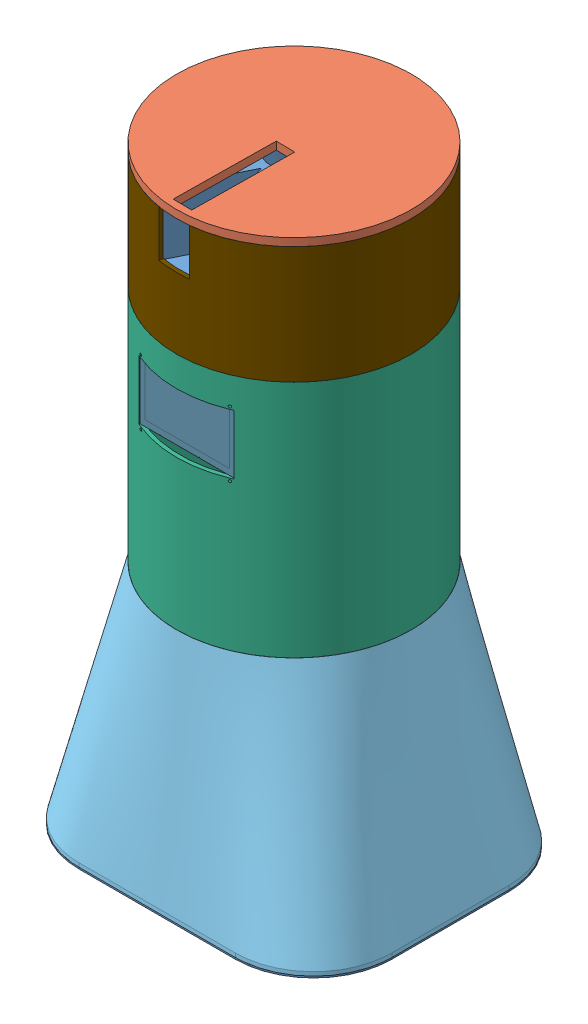
SolidWorks assembly Main Assembly, configuration Default. Lengths in mm.
Overall size (428.69 805.97 406.23).
32 component instances, 21 part files, 30 mates.
Components (placement in the parent):
- Base-1: Base [Default] at (-9.7695 -23.298 20.3041) size (400 2 350)
- Wheel-1: Wheel [Default] at (-159.7695 3.702 20.3041) x (0 -0.4051 0.914272) z (-1 0 0) size (100 100 35)
- Wheel-2: Wheel [Default] at (140.2305 3.702 20.3041) x (0 0.318897 -0.947789) z (1 0 0) size (100 100 35)
- MINEBEA 05701607 stepper motor.step-1: MINEBEA 05701607 stepper motor.step [Default] at (-120.6195 3.702 20.3041) x (0 0 -1) z (-1 0 0) size (42 48.2 62.55)
- MINEBEA 05701607 stepper motor.step-2: MINEBEA 05701607 stepper motor.step [Default] at (101.0805 3.702 20.3041) x (0 0 1) z (1 0 0) size (42 48.2 62.55)
- Nema 17 bracket-1: Nema 17 bracket [Default] at (-122.6195 3.702 20.3041) x (0 0 1) z (-1 0 0) size (40 50 40)
- Nema 17 bracket-2: Nema 17 bracket [Default] at (103.0805 3.702 20.3041) x (0 0 -1) z (1 0 0) size (40 50 40)
- Base Cover-1: Base Cover [Default] at (-9.7695 -21.298 20.3041) size (428.69 300.01 378.81)
- Mid Cover-1: Mid Cover [Default] at (-9.7695 278.702 20.3041) size (300 305 300)
- ER-TFTV050A3-3_3D.step-2: ER-TFTV050A3-3_3D.step [Default] at (-66.6994 466.0367 151.0649) size (121.88 89.8 12.7)
  - Default.step-1: Default.step [Default] at origin size (121.88 89.8 12.7)
    - Micro-USB-1.step-1: Micro-USB-1.step [Default] at (115.1584 26.8063 -1.07) x (0 -1 0) z (1 0 0) size (7.98 2.76 5.43)
    - Micro-USB-1.step-2: Micro-USB-1.step [Default] at (115.1026 41.8572 -1.07) x (0 -1 0) z (1 0 0) size (7.98 2.76 5.43)
    - HDMI_卡座-1.step-1: HDMI_卡座-1.step [Default] at (118.3814 62.6862 -1.07) x (0 -1 0) z (1 0 0) size (15.08 8.38 12.15)
    - XPT2046-1.step-1: XPT2046-1.step [Default] at (96.2836 29.7423 -0.098) x (0 -1 0) z (0 0 -1) size (5.58 5.58 1.35)
    - XPT2046-1.step-2: XPT2046-1.step [Default] at (96.7433 37.2781 -0.098) x (0 -1 0) z (0 0 -1) size (5.58 5.58 1.35)
    - 连接器_50-Pin-1.step-1: 连接器_50-Pin-1.step [Default] at (33.4715 47.6211 -0.8) x (1 0 0) z (0 0 -1) size (25.97 6.45 2.13)
    - 拨动开关-2.step-1: 拨动开关-2.step [Default] at (109.6588 14.0139 -2.551) x (0 1 0) z (1 0 0) size (9.25 3.5 8.04)
    - FLASH_IC-1.step-1: FLASH_IC-1.step [Default] at (50.1709 65.5261 -1.6531) x (0 -1 0) z (1 0 0) size (5.63 2.58 8.9)
    - 043A3-050A3-3 IC-2.step-1: 043A3-050A3-3 IC-2.step [Default] at (61.6363 43.8941 -1) x (0 -1 0) z (1 0 0) size (24.4 2.6 19.54)
    - V050A3-3-1.step-1: V050A3-3-1.step [Default] at origin size (120.9 89.8 7)
    - 连接器_6-Pin-1.step-1: 连接器_6-Pin-1.step [Default] at (81.4816 49.8598 -0.8) x (-1 0 0) z (0 0 -1) size (10.37 5.52 2)
    - ER-TFTV043A3-3开关 - 副本-1.step-1: ER-TFTV043A3-3开关 - 副本-1.step [Default] at (0.6995 12.4598 -2.2219) x (0 0 1) z (-1 0 0) size (2.85 7.04 5.23)
    - ER-TFTV043A3-3开关 - 副本-1.step-2: ER-TFTV043A3-3开关 - 副本-1.step [Default] at (0.6995 23.4598 -2.2219) x (0 0 1) z (-1 0 0) size (2.85 7.04 5.23)
    - ER-TFTV043A3-3开关 - 副本-1.step-3: ER-TFTV043A3-3开关 - 副本-1.step [Default] at (0.6995 34.4598 -2.2219) x (0 0 1) z (-1 0 0) size (2.85 7.04 5.23)
    - ER-TFTV043A3-3开关 - 副本-1.step-4: ER-TFTV043A3-3开关 - 副本-1.step [Default] at (0.6995 45.4598 -2.2219) x (0 0 1) z (-1 0 0) size (2.85 7.04 5.23)
- Mid Plate-1: Mid Plate [Default] at (-9.7695 285.702 20.3041) x (1 0 0) z (0 -1 0) size (288 288 2)
- dispenser-1: dispenser [Default] at (276.6087 461.337 -65.9211) x (-0.098072 0 0.995179) z (-0.995179 0 -0.098072) size (371.58 150 371.58)
  - medicine dispenser shwll-1: medicine dispenser shwll [Default] at (113.8952 122.365 276.5413) x (1 0 0) z (0 1 0) size (300 300 150)
  - medicine dispenser roatating part-1: medicine dispenser roatating part [Default] at (113.8952 177.365 276.5413) x (0.934657 0 0.35555) z (-0.35555 0 0.934657) size (288 94 288)
  - medicine dispenser lid-1: medicine dispenser lid [Default] at (113.8952 272.365 276.5413) x (0.085182 0 0.996365) z (-0.996365 0 0.085182) size (300 10 300)
- rod-1: rod [Default] at (-9.5195 278.702 20.0541) size (20 600 20)
Mates (geometry in assembly coordinates):
- Coincident1: coincident anti-aligned: plane of Base-1 through (-9.7695 -21.298 20.3041) normal (0 1 0); plane of Nema 17 bracket-1 through (-122.6195 -21.298 20.3041) normal (0 -1 0)
- Concentric1: concentric aligned: cylinder of MINEBEA 05701607 stepper motor.step-1 through (-120.6195 -11.798 35.8041) axis (1 0 0) radius 1.25; cylinder of Nema 17 bracket-1 through (-122.6205 -11.798 35.8041) axis (1 0 0) radius 1.4
- Concentric2: concentric aligned: cylinder of MINEBEA 05701607 stepper motor.step-1 through (-120.6195 19.202 4.8041) axis (1 0 0) radius 1.25; cylinder of Nema 17 bracket-1 through (-122.6205 19.202 4.8041) axis (1 0 0) radius 1.4
- Coincident2: coincident anti-aligned: plane of MINEBEA 05701607 stepper motor.step-1 through (-120.6195 3.702 20.3041) normal (-1 0 0); plane of Nema 17 bracket-1 through (-120.6195 3.702 20.3041) normal (1 0 0)
- Concentric3: concentric aligned: cylinder of Wheel-1 through (-169.7705 3.702 20.3041) axis (1 0 0) radius 3; cylinder of MINEBEA 05701607 stepper motor.step-1 through (-144.7695 3.702 20.3041) axis (1 0 0) radius 2.5
- Distance1: distance = 10 mm anti-aligned: plane of Wheel-1 through (-134.7695 3.702 20.3041) normal (1 0 0); plane of MINEBEA 05701607 stepper motor.step-1 through (-144.7695 3.702 20.3041) normal (-1 0 0)
- Width1: width anti-aligned: plane of Base-1 through (-144.7695 -23.299 -54.6959) normal (-1 0 0); plane of Wheel-1 through (-174.7695 -23.299 -54.6959) normal (1 0 0); plane of Base-1 through (-149.7695 3.702 20.3041) normal (1 0 0); plane of Wheel-1 through (-169.7695 3.702 20.3041) normal (-1 0 0)
- Width2: width aligned: plane of Base-1 through (-209.7695 -21.298 195.3041) normal (0 0 1); plane of Nema 17 bracket-1 through (-209.7695 -21.298 -154.6959) normal (0 0 -1); plane of Base-1 through (-120.6195 -21.298 40.3041) normal (0 0 1); plane of Nema 17 bracket-1 through (-82.6195 -21.298 0.3041) normal (0 0 -1)
- Width3: width aligned: plane of Base-1 through (-209.7695 -21.298 195.3041) normal (0 0 1); plane of Nema 17 bracket-2 through (-209.7695 -21.298 -154.6959) normal (0 0 -1); plane of Base-1 through (63.0805 -21.298 40.3041) normal (0 0 1); plane of Nema 17 bracket-2 through (101.0805 -21.298 0.3041) normal (0 0 -1)
- Coincident3: coincident anti-aligned: plane of Base-1 through (-9.7695 -21.298 20.3041) normal (0 1 0); plane of Nema 17 bracket-2 through (103.0805 -21.298 20.3041) normal (0 -1 0)
- Concentric4: concentric aligned: cylinder of MINEBEA 05701607 stepper motor.step-2 through (101.0805 -11.798 4.8041) axis (-1 0 0) radius 1.25; cylinder of Nema 17 bracket-2 through (103.0815 -11.798 4.8041) axis (-1 0 0) radius 1.4
- Concentric5: concentric aligned: cylinder of MINEBEA 05701607 stepper motor.step-2 through (101.0805 19.202 35.8041) axis (-1 0 0) radius 1.25; cylinder of Nema 17 bracket-2 through (103.0815 19.202 35.8041) axis (-1 0 0) radius 1.4
- Coincident4: coincident anti-aligned: plane of MINEBEA 05701607 stepper motor.step-2 through (101.0805 3.702 20.3041) normal (1 0 0); plane of Nema 17 bracket-2 through (101.0805 3.702 20.3041) normal (-1 0 0)
- Concentric6: concentric aligned: cylinder of Wheel-2 through (150.2315 3.702 20.3041) axis (-1 0 0) radius 3; cylinder of MINEBEA 05701607 stepper motor.step-2 through (125.2305 3.702 20.3041) axis (-1 0 0) radius 2.5
- Distance2: distance = 10 mm anti-aligned: plane of Wheel-2 through (115.2305 3.702 20.3041) normal (-1 0 0); plane of MINEBEA 05701607 stepper motor.step-2 through (125.2305 3.702 20.3041) normal (1 0 0)
- Width4: width anti-aligned: plane of Base-1 through (125.2305 -23.299 -54.6959) normal (1 0 0); plane of Wheel-2 through (155.2305 -23.299 -54.6959) normal (-1 0 0); plane of Base-1 through (130.2305 3.702 20.3041) normal (-1 0 0); plane of Wheel-2 through (150.2305 3.702 20.3041) normal (1 0 0)
- Coincident5: coincident anti-aligned: plane of Base-1 through (-9.7695 -21.298 20.3041) normal (0 1 0); plane of Base Cover-1 through (90.2305 -21.298 95.3041) normal (0 -1 0)
- Coincident6: coincident aligned: plane of Base-1 through (-209.7695 -21.298 195.3041) normal (0 0 1); plane of Base Cover-1 through (-109.7695 -16.298 195.3041) normal (0 0 1)
- Coincident7: coincident aligned: plane of Base-1 through (190.2305 -21.298 -154.6959) normal (1 0 0); plane of Base Cover-1 through (190.2305 -16.298 -54.6959) normal (1 0 0)
- Concentric7: concentric anti-aligned: circle of Base Cover-1; cylinder of Mid Cover-1 through (-9.7695 283.702 20.3041) axis (0 -1 0) radius 150
- Coincident8: coincident anti-aligned: plane of Base Cover-1 through (-9.7695 278.702 20.3041) normal (0 1 0); plane of Mid Cover-1 through (-9.7695 278.702 20.3041) normal (0 -1 0)
- Coincident9: coincident aligned: plane of Base Cover-1 through (-9.7695 -21.298 20.3041) normal (0 0 1); plane of Mid Cover-1 through (-9.7695 278.702 20.3041) normal (0 0 1)
- Coincident13: coincident anti-aligned: plane of Mid Cover-1 through (-9.7695 283.702 20.3041) normal (0 1 0); plane of Mid Plate-1 through (-9.7695 283.702 20.3041) normal (0 -1 0)
- Concentric8: concentric anti-aligned: cylinder of Mid Cover-1 through (-9.7695 283.702 20.3041) axis (0 -1 0) radius 150; cylinder of Mid Plate-1 through (-9.7695 283.702 20.3041) axis (0 1 0) radius 144
- Concentric9: concentric aligned: cylinder of Mid Cover-1 through (-9.7695 283.702 20.3041) axis (0 -1 0) radius 150; cylinder of dispenser-1/medicine dispenser shwll-1 through (-9.7695 733.702 20.3041) axis (0 -1 0) radius 150
- Coincident14: coincident anti-aligned: plane of Mid Cover-1 through (-9.7695 583.702 20.3041) normal (0 1 0); plane of dispenser-1/medicine dispenser shwll-1 through (-9.7695 583.702 20.3041) normal (0 -1 0)
- Coincident15: coincident: plane of Mid Plate-1 through (-20.0195 283.702 10.0541) normal (0 0 1); plane of rod-1 through (-19.5195 1240.4125 10.0541) normal (0 0 -1)
- Coincident16: coincident: plane of Mid Plate-1 through (0.4805 283.702 30.5541) normal (-1 0 0); plane of rod-1 through (0.4805 1240.4125 10.0541) normal (1 0 0)
- Coincident17: coincident aligned: plane of Base Cover-1 through (-9.7695 -21.298 20.3041) normal (1 0 0); plane of Mid Plate-1 through (-9.7695 285.702 20.3041) normal (1 0 0)
- Coincident18: coincident anti-aligned: plane of Base-1 through (-9.7695 -21.298 20.3041) normal (0 1 0); plane of rod-1 through (-9.5195 -21.298 20.0541) normal (0 -1 0)
